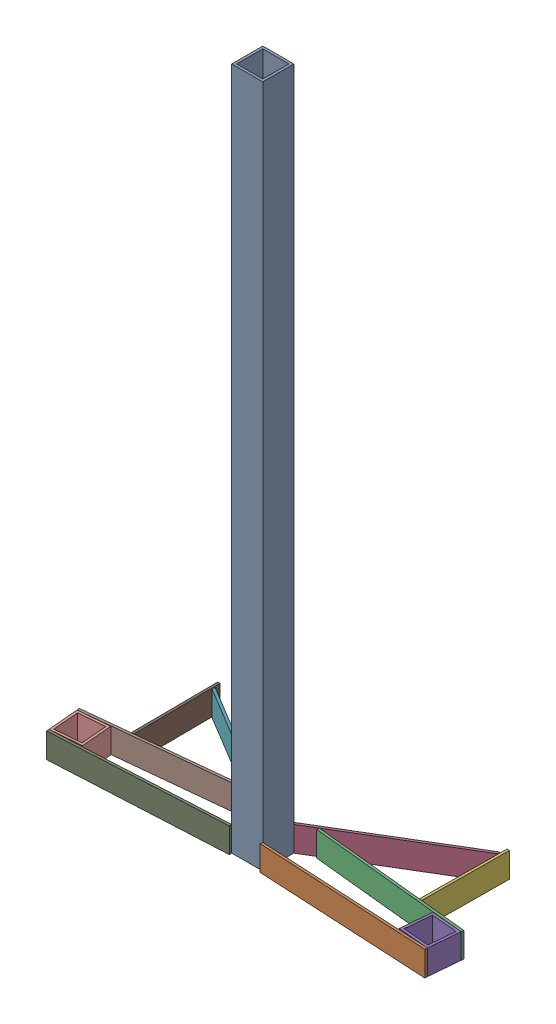
SolidWorks assembly LSТСБ, configuration По умолчанию. Lengths in mm.
Overall size (309.38 550 102.94).
11 component instances, 6 part files, 17 mates.
Components (placement in the parent):
- Основание25-1: Основание25 [По умолчанию] at (0 0 -12.5) size (25 550 25)
- П1-1: П1 [По умолчанию] at (12.5 20 0) x (0.99863 0 0.052336) z (-0.052336 0 0.99863) size (140 20 2)
- П2-1: П2 [По умолчанию] at (25.3571 20 -32.7262) x (0.994864 0 0.10122) z (-0.10122 0 0.994864) size (130 20 2)
- П3-1: П3 [По умолчанию] at (11.4698 20 -26.7143) x (0.857143 0 -0.515079) z (0.515079 0 0.857143) size (120 20 2)
- Бобышка25-1: Бобышка25 [По умолчанию] at (140.9451 0 -6.2148) x (0.996195 0 0.087156) z (-0.087156 0 0.996195) size (25 20 25)
- П22-2: П22 [По умолчанию] at (117.4069 20 -93.5999) x (-0.007314 0 0.999973) z (-0.999973 0 -0.007314) size (70 20 2)
- П3-2: П3 [По умолчанию] at (-12.5 20 -25) x (-0.857143 0 -0.515079) z (0.515079 0 -0.857143) size (120 20 2)
- П2-3: П2 [По умолчанию] at (-25.1547 20 -30.7365) x (-0.994864 0 0.10122) z (-0.10122 0 -0.994864) size (130 20 2)
- П1-2: П1 [По умолчанию] at (-12.3953 20 1.9973) x (-0.99863 0 0.052336) z (-0.052336 0 -0.99863) size (140 20 2)
- Бобышка25-2: Бобышка25 [По умолчанию] at (-140.9451 0 -6.2148) x (-0.996195 0 0.087156) z (-0.087156 0 -0.996195) size (25 20 25)
- П22-3: П22 [По умолчанию] at (-115.4069 20 -93.6145) x (0.007314 0 0.999973) z (-0.999973 0 0.007314) size (70 20 2)
Mates (geometry in assembly coordinates):
- Совпадение4: coincident aligned: plane of Основание25-1 through (0 0 -12.5) normal (0 -1 0); plane of П1-1 through (12.3953 0 1.9973) normal (0 -1 0)
- Совпадение5: coincident aligned: line of Основание25-1 through (12.5 550 0) axis (0 -1 0); line of П1-1 through (12.5 20 0) axis (0 -1 0)
- Угол1: planar angle = 1.623156 rad anti-aligned: plane of Основание25-1 through (12.5 550 0) normal (1 0 0); plane of П1-1 through (12.5 20 0) normal (0.052336 0 -0.99863)
- Совпадение7: coincident aligned: plane of П1-1 through (12.3953 0 1.9973) normal (0 -1 0); plane of П2-1 through (25.1547 0 -30.7365) normal (0 -1 0)
- Совпадение8: coincident aligned: line of Основание25-1 through (12.5 550 -25) axis (0 -1 0); line of П3-1 through (12.5 20 -25) axis (0 -1 0)
- Совпадение9: coincident aligned: plane of Основание25-1 through (0 0 -12.5) normal (0 -1 0); plane of П3-1 through (12.5 0 -25) normal (0 -1 0)
- Совпадение10: coincident: line of П2-1 through (25.3571 20 -32.7262) axis (0 -1 0); plane of П3-1 through (12.5 20 -25) normal (0.515079 0 0.857143)
- Расстояние2: distance = 10 mm: line of П2-1 through (25.3571 20 -32.7262) axis (0 -1 0); line of П3-1 through (12.5 20 -25) axis (0 -1 0)
- Совпадение12: coincident aligned: plane of Основание25-1 through (0 0 -12.5) normal (0 -1 0); plane of Бобышка25-1 through (140.9451 0 -6.2148) normal (0 -1 0)
- Совпадение13: coincident anti-aligned: line of П2-1 through (154.487 0 -17.5778) axis (0 1 0); line of Бобышка25-1 through (154.487 20 -17.5778) axis (0 -1 0)
- Совпадение14: coincident anti-aligned: line of П1-1 through (152.3081 0 7.327) axis (0 1 0); line of Бобышка25-1 through (152.3081 20 7.327) axis (0 -1 0)
- Угол3: planar angle = 0.034907 rad anti-aligned: plane of Бобышка25-1 through (127.4033 20 5.1481) normal (-0.087156 0 0.996195); plane of П1-1 through (12.5 20 0) normal (0.052336 0 -0.99863)
- Совпадение17: coincident aligned: plane of Основание25-1 through (0 0 -12.5) normal (0 -1 0); plane of П22-2 through (115.4069 0 -93.6145) normal (0 -1 0)
- Совпадение18: coincident: line of П3-1 through (115.3571 0 -86.8095) axis (0 1 0); plane of П22-2 through (115.4069 20 -93.6145) normal (-0.999973 0 -0.007314)
- Совпадение19: coincident: plane of П2-1 through (25.3571 20 -32.7262) normal (0.10122 0 -0.994864); line of П22-2 through (114.8949 0 -23.6164) axis (0 1 0)
- Расстояние3: distance = 40 mm: line of П22-2 through (114.8949 0 -23.6164) axis (0 1 0); line of П2-1 through (154.6895 0 -19.5676) axis (0 1 0)
- Расстояние4: distance = 15 mm: line of П2-1 through (25.3571 20 -32.7262) axis (0 -1 0); line of П3-1 through (12.5 20 -25) axis (0 -1 0)
